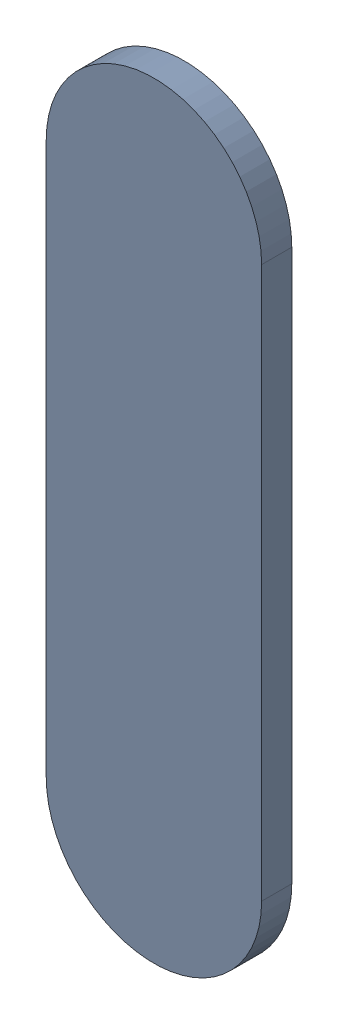
SolidWorks assembly Track (28.05mm,41.5mm)(28.05mm,42.15mm) on Top Layer, configuration Predeterminado. Lengths in mm.
Overall size (0.25 0.9 0.04).
2 component instances, 1 part files, 0 mates.
Components (placement in the parent):
- Track (28.05mm,41.5mm)(28.05mm,42.15mm) on Top Layer-1-1: Track (28.05mm,41.5mm)(28.05mm,42.15mm) on Top Layer-1 [Predeterminado] at (-68.317 -44.187 -0.0457) size (0.25 0.9 0.04)
  - Track (28.05mm,41.5mm)(28.05mm,42.15mm) on Top Layer-Part-1-1: Track (28.05mm,41.5mm)(28.05mm,42.15mm) on Top Layer-Part-1 [Predeterminado] at origin size (0.25 0.9 0.04)
